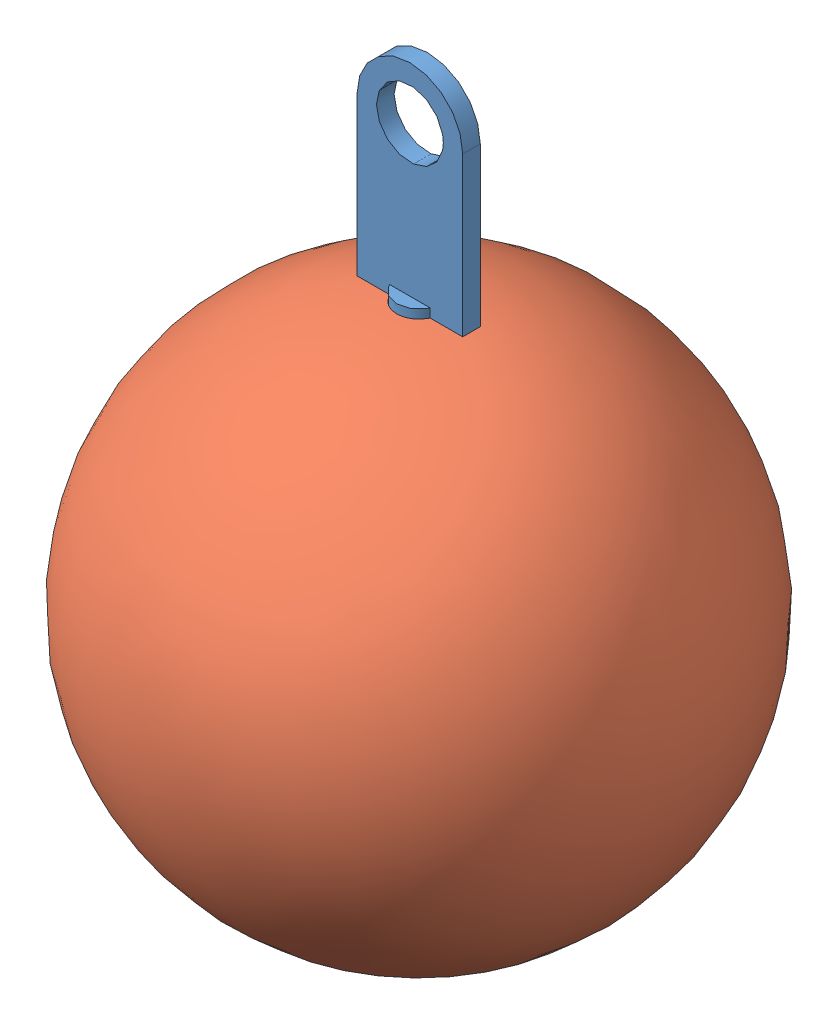
SolidWorks assembly Weight-Hook, configuration Default. Lengths in mm.
Overall size (38.1 53.27 38.1).
2 component instances, 2 part files, 3 mates.
Components (placement in the parent):
- Eye Hook-1: Eye Hook [Default] at origin size (7.62 27.94 3.17)
- Weight-1: Weight [Default] at (0 -11.3648 0) size (38.1 38.03 38.1)
Mates (geometry in assembly coordinates):
- Concentric2: concentric aligned: cylinder of Eye Hook-1 through (0 8.255 0) axis (0 -1 0) radius 1.5875; cylinder of Weight-1 through (0 7.6852 0) axis (0 -1 0) radius 1.5748
- Tangent1: tangent: plane of Eye Hook-1 through (-3.81 7.62 0.635) normal (0 -1 0); circle of Weight-1
- Parallel1: parallel anti-aligned: plane of Eye Hook-1 through (0 -5.08 0) normal (0 -1 0); plane of Weight-1 through (0 -11.3648 0) normal (0 1 0)
